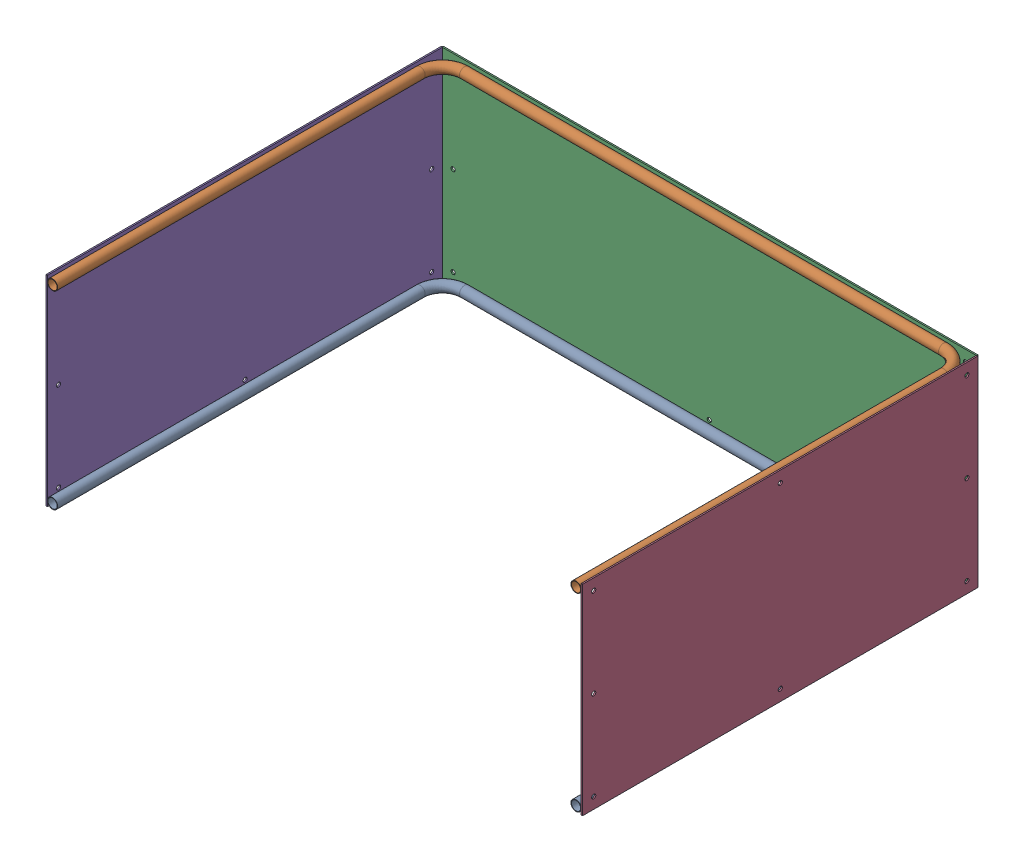
SolidWorks assembly GE-16090_ASM, configuration Default. Lengths in mm.
Overall size (1223.57 457.2 903.88).
5 component instances, 3 part files, 0 mates.
Components (placement in the parent):
- GE-16091-1: GE-16091 [Default] at origin size (1217.22 23.42 900.71)
- GE-16091-2: GE-16091 [Default] at (0 431.8 0) size (1217.22 23.42 900.71)
- GE-16092-1: GE-16092 [Default] at (0 215.9 -903.8844) size (1219.2 457.2 3.17)
- GE-16093-1: GE-16093 [Default] at (611.7844 215.9 -450.85) x (0 0 1) z (-1 0 0) size (901.7 457.2 3.17)
- GE-16093-2: GE-16093 [Default] at (-611.7844 215.9 -450.85) x (0 0 -1) z (1 0 0) size (901.7 457.2 3.17)
